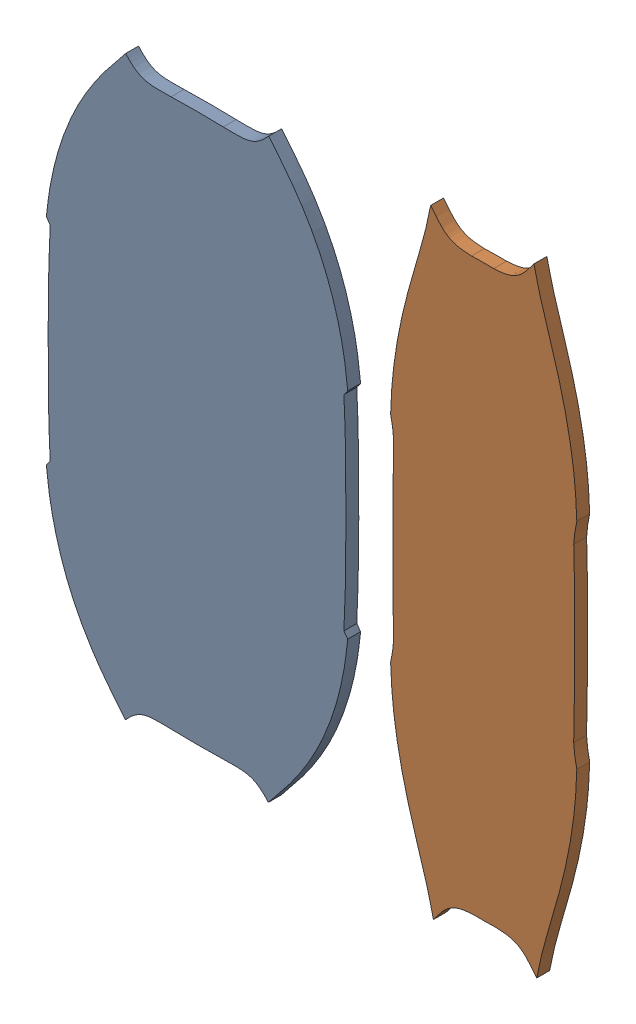
SolidWorks assembly ARBTSB, configuration По умолчанию. Lengths in mm.
Overall size (224.7 167.83 3).
2 component instances, 2 part files, 5 mates.
Components (placement in the parent):
- ARBOMT-1: ARBOMT [По умолчанию] at (-38.2573 22.3897 -2.9999) x (0.690743 -0.723101 0) z (0 0 1) size (120.26 117.07 3)
- ART-1: ART [По умолчанию] at (-8.859 50.2765 -2.9999) x (0.86911 -0.494619 0) z (0 0 1) size (92.51 136.8 3)
Mates (geometry in assembly coordinates):
- Совпадение6: coincident: point of ARBOMT-1
- Совпадение7: coincident: unknown of ARBOMT-1
- Совпадение8: coincident aligned: plane of ARBOMT-1 through (-64.5919 -34.8737 0.0001) normal (0 0 1); plane of ART-1 through (49.9648 62.0443 0.0001) normal (0 0 1)
- Расстояние1: distance = 10 mm: point of ART-1; point of ARBOMT-1
- Расстояние2: distance = 10 mm: point of ART-1; point of ARBOMT-1
